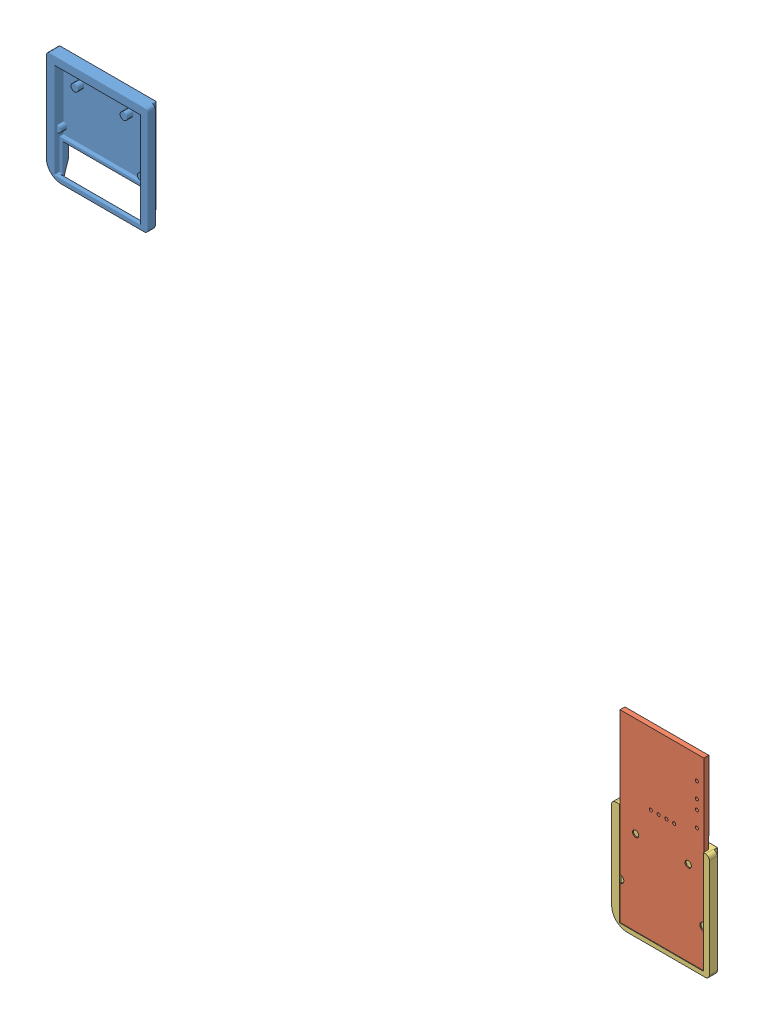
SolidWorks assembly cartridge_assembly, configuration Default. Lengths in mm.
Overall size (213.75 156.18 5.99).
5 component instances, 3 part files, 3 mates.
Components (placement in the parent):
- catridge-1: catridge [Default] at (-55.7762 69.5341 0.2862) size (33 35 3.75)
- dsi_esp-1: dsi_esp [Default] at origin size (27.32 60.03 1.6)
  - dsi_esp.step-1: dsi_esp.step [Default] at origin size (27.32 60.03 1.6)
    - dsi_esp_PCB.step-1: dsi_esp_PCB.step [Default] at origin size (27.32 60.03 1.6)
- print_cartridge-1: print_cartridge [Default] at (0 0 1.6) size (31.85 34.87 3.73)
Mates (geometry in assembly coordinates):
- Concentric1: concentric aligned: cylinder of dsi_esp-1/dsi_esp.step-1/dsi_esp_PCB.step-1 through (121.275 -72.675 0) axis (0 0 -1) radius 1.0213; cylinder of print_cartridge-1 through (121.275 -72.675 1.27) axis (0 0 -1) radius 1.0213
- Concentric2: concentric aligned: circle of dsi_esp-1/dsi_esp.step-1/dsi_esp_PCB.step-1; circle of print_cartridge-1
- Distance1: distance = 1.27 mm anti-aligned: plane of print_cartridge-1 through (121.275 -72.675 1.27) normal (0 0 1); plane of dsi_esp-1/dsi_esp.step-1/dsi_esp_PCB.step-1 through (0 0 0) normal (0 0 -1)
